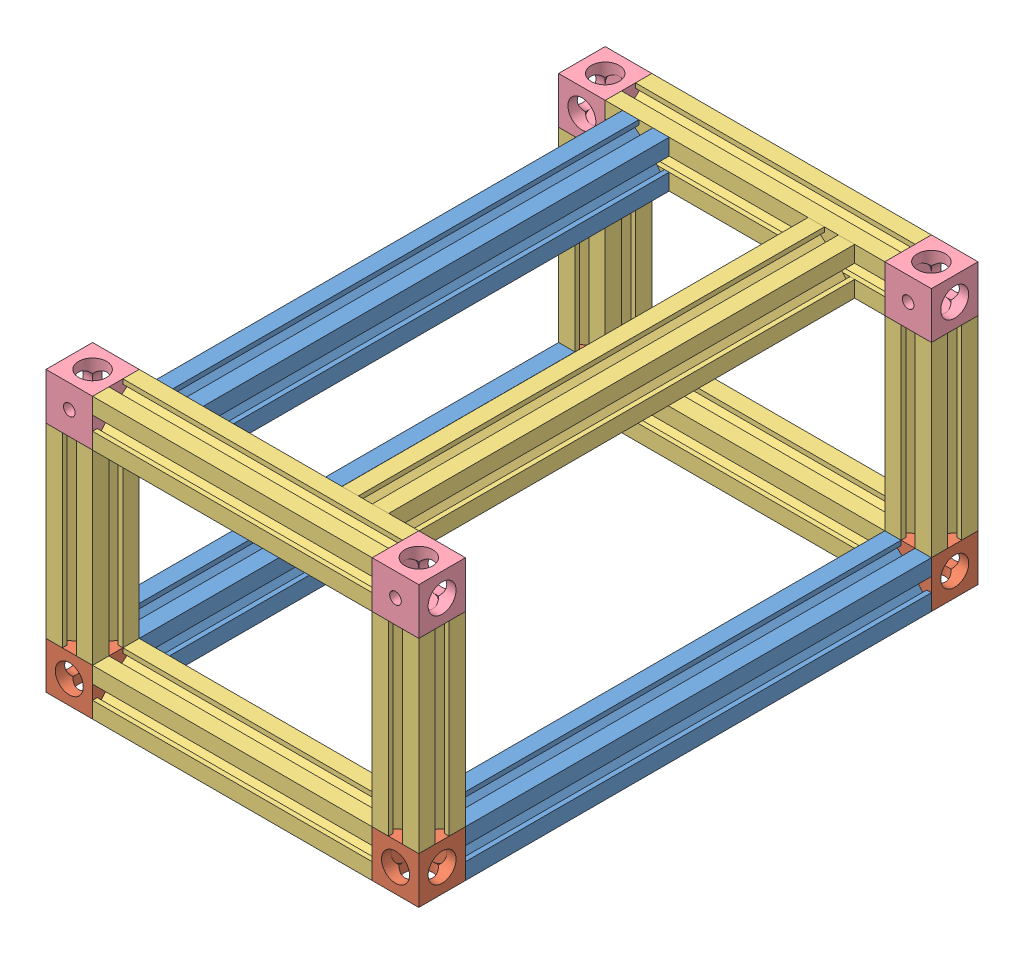
SolidWorks assembly Cabine, configuration Défaut. Lengths in mm.
Overall size (80 60 120).
20 component instances, 4 part files, 62 mates.
Components (placement in the parent):
- MakerBeam10x10x100-1: MakerBeam10x10x100 [Default] at origin size (10 10 100)
- MakerBeam10x10x100-2: MakerBeam10x10x100 [Default] at (-13.727 -50 0) size (10 10 100)
- MakerBeam10x10x100-3: MakerBeam10x10x100 [Default] at (56.273 -50 0) size (10 10 100)
- MakerBeamCornerCube-1: MakerBeamCornerCube [Default] at (61.273 -45 0) x (0 -1 0) z (0 0 -1) size (10 10 10)
- MakerBeamCornerCube-2: MakerBeamCornerCube [Default] at (-8.727 -55 0) x (-1 0 0) z (0 0 -1) size (10 10 10)
- MakerBeamCornerCube-3: MakerBeamCornerCube [Default] at (51.273 -55 100) size (10 10 10)
- MakerBeamCornerCube-4: MakerBeamCornerCube [Default] at (-18.727 -45 100) x (0 -1 0) z (0 0 1) size (10 10 10)
- Makerbeam50-1000mm-1: Makerbeam50-1000mm [60mm] at (51.273 -50 105) x (0 -1 0) z (-1 0 0) size (10 10 60)
- Makerbeam50-1000mm-2: Makerbeam50-1000mm [60mm] at (-8.727 -50 -5) x (0 1 0) z (1 0 0) size (10 10 60)
- Makerbeam50-1000mm-3: Makerbeam50-1000mm [60mm] at (-8.727 0 105) x (0 0 -1) z (1 0 0) size (10 10 60)
- Makerbeam50-1000mm-4: Makerbeam50-1000mm [60mm] at (51.273 0 -5) x (0 0 1) z (-1 0 0) size (10 10 60)
- MakerBeam-cube-1: MakerBeam-cube [Default] at (51.273 0 105) x (0 0 -1) z (1 0 0) size (10 10 10)
- MakerBeam-cube-2: MakerBeam-cube [Default] at (-8.727 0 -5) x (0 0 1) z (-1 0 0) size (10 10 10)
- MakerBeam-cube-3: MakerBeam-cube [Default] at (51.273 0 -5) x (0 0 -1) z (1 0 0) size (10 10 10)
- MakerBeam-cube-4: MakerBeam-cube [Default] at (-8.727 0 105) x (0 1 0) z (-1 0 0) size (10 10 10)
- Makerbeam50-1000mm-5: Makerbeam50-1000mm [40mm] at (56.273 -5 105) x (1 0 0) z (0 -1 0) size (10 10 40)
- Makerbeam50-1000mm-6: Makerbeam50-1000mm [40mm] at (-13.727 -5 105) x (1 0 0) z (0 -1 0) size (10 10 40)
- Makerbeam50-1000mm-7: Makerbeam50-1000mm [40mm] at (-13.727 -5 -5) x (1 0 0) z (0 -1 0) size (10 10 40)
- Makerbeam50-1000mm-8: Makerbeam50-1000mm [40mm] at (56.273 -5 -5) x (1 0 0) z (0 -1 0) size (10 10 40)
- Makerbeam50-1000mm-9: Makerbeam50-1000mm [100mm] at (39.8053 0 0) size (10 10 100)
Mates (geometry in assembly coordinates):
- Coïncidente1: coincident aligned: plane of MakerBeam10x10x100-1 through (0 0 0) normal (0 0 1); plane of assembly through (0 0 0) normal (0 0 1)
- Coïncidente2: coincident aligned: plane of MakerBeam10x10x100-1 through (0 0 0) normal (0 1 0); plane of assembly through (0 0 0) normal (0 1 0)
- Coïncidente3: coincident aligned: plane of MakerBeam10x10x100-1 through (0 0 0) normal (1 0 0); plane of assembly through (0 0 0) normal (1 0 0)
- Coïncidente4: coincident anti-aligned: plane of MakerBeam10x10x100-3 through (56.273 -50 100) normal (0 0 1); plane of MakerBeamCornerCube-3 through (51.273 -55 100) normal (0 0 -1)
- Coaxiale1: concentric anti-aligned: cylinder of MakerBeam10x10x100-3 through (56.273 -50 100) axis (0 0 -1) radius 1.25; cylinder of MakerBeamCornerCube-3 through (56.273 -50 100) axis (0 0 1) radius 1.5
- Coïncidente5: coincident anti-aligned: plane of MakerBeam10x10x100-3 through (56.273 -50 0) normal (0 0 -1); plane of MakerBeamCornerCube-1 through (61.273 -45 0) normal (0 0 1)
- Coaxiale2: concentric aligned: cylinder of MakerBeam10x10x100-3 through (56.273 -50 100) axis (0 0 -1) radius 1.25; cylinder of MakerBeamCornerCube-1 through (56.273 -50 0) axis (0 0 -1) radius 1.5
- Coïncidente6: coincident anti-aligned: plane of MakerBeam10x10x100-2 through (-13.727 -50 0) normal (0 0 -1); plane of MakerBeamCornerCube-2 through (-8.727 -55 0) normal (0 0 1)
- Coaxiale3: concentric aligned: cylinder of MakerBeam10x10x100-2 through (-13.727 -50 100) axis (0 0 -1) radius 1.25; cylinder of MakerBeamCornerCube-2 through (-13.727 -50 0) axis (0 0 -1) radius 1.5
- Coaxiale4: concentric anti-aligned: cylinder of MakerBeam10x10x100-2 through (-13.727 -50 100) axis (0 0 -1) radius 1.25; cylinder of MakerBeamCornerCube-4 through (-13.727 -50 100) axis (0 0 1) radius 1.5
- Coïncidente7: coincident anti-aligned: plane of MakerBeam10x10x100-2 through (-13.727 -50 100) normal (0 0 1); plane of MakerBeamCornerCube-4 through (-18.727 -45 100) normal (0 0 -1)
- Coïncidente8: coincident anti-aligned: plane of MakerBeamCornerCube-4 through (-8.727 -45 110) normal (1 0 0); plane of Makerbeam50-1000mm-1 through (-8.727 -50 105) normal (-1 0 0)
- Coaxiale5: concentric anti-aligned: cylinder of MakerBeamCornerCube-4 through (-8.727 -50 105) axis (-1 0 0) radius 1.5; cylinder of Makerbeam50-1000mm-1 through (-8.727 -50 105) axis (1 0 0) radius 1.25
- Coaxiale6: concentric aligned: cylinder of MakerBeamCornerCube-3 through (51.273 -50 105) axis (1 0 0) radius 1.5; cylinder of Makerbeam50-1000mm-1 through (-8.727 -50 105) axis (1 0 0) radius 1.25
- Coïncidente9: coincident anti-aligned: plane of MakerBeamCornerCube-3 through (51.273 -55 110) normal (-1 0 0); plane of Makerbeam50-1000mm-1 through (51.273 -50 105) normal (1 0 0)
- Coaxiale7: concentric anti-aligned: cylinder of MakerBeamCornerCube-1 through (51.273 -50 -5) axis (1 0 0) radius 1.5; cylinder of Makerbeam50-1000mm-2 through (51.273 -50 -5) axis (-1 0 0) radius 1.25
- Coïncidente10: coincident anti-aligned: plane of MakerBeamCornerCube-1 through (51.273 -45 -10) normal (-1 0 0); plane of Makerbeam50-1000mm-2 through (51.273 -50 -5) normal (1 0 0)
- Coaxiale9: concentric aligned: cylinder of MakerBeamCornerCube-2 through (-8.727 -50 -5) axis (-1 0 0) radius 1.5; cylinder of Makerbeam50-1000mm-2 through (51.273 -50 -5) axis (-1 0 0) radius 1.25
- Coïncidente12: coincident anti-aligned: plane of MakerBeamCornerCube-2 through (-8.727 -55 -10) normal (1 0 0); plane of Makerbeam50-1000mm-2 through (-8.727 -50 -5) normal (-1 0 0)
- Coïncidente13: coincident aligned: plane of Makerbeam50-1000mm-2 through (51.273 -45 0) normal (0 1 0); plane of MakerBeamCornerCube-2 through (-8.727 -45 -10) normal (0 1 0)
- Coïncidente14: coincident aligned: plane of MakerBeam10x10x100-2 through (-8.727 -45 100) normal (0 1 0); plane of MakerBeamCornerCube-2 through (-8.727 -45 -10) normal (0 1 0)
- Coïncidente15: coincident aligned: plane of MakerBeam10x10x100-3 through (51.273 -45 100) normal (0 1 0); plane of MakerBeamCornerCube-1 through (61.273 -45 -10) normal (0 1 0)
- Coïncidente16: coincident aligned: plane of MakerBeamCornerCube-1 through (61.273 -45 -10) normal (0 1 0); plane of Makerbeam50-1000mm-2 through (51.273 -45 -6.5) normal (0 1 0)
- Coïncidente17: coincident aligned: plane of MakerBeamCornerCube-3 through (51.273 -45 110) normal (0 1 0); plane of Makerbeam50-1000mm-1 through (-8.727 -45 100) normal (0 1 0)
- Coïncidente18: coincident aligned: plane of MakerBeam10x10x100-3 through (51.273 -45 100) normal (0 1 0); plane of MakerBeamCornerCube-3 through (51.273 -45 110) normal (0 1 0)
- Coïncidente19: coincident aligned: plane of MakerBeamCornerCube-4 through (-18.727 -45 110) normal (0 1 0); plane of Makerbeam50-1000mm-1 through (-8.727 -45 100) normal (0 1 0)
- Coïncidente21: coincident aligned: plane of MakerBeam10x10x100-2 through (-8.727 -45 100) normal (0 1 0); plane of MakerBeamCornerCube-4 through (-18.727 -45 110) normal (0 1 0)
- Coïncidente22: coincident anti-aligned: plane of Makerbeam50-1000mm-3 through (51.273 0 105) normal (1 0 0); plane of MakerBeam-cube-1 through (51.273 0 105) normal (-1 0 0)
- Coaxiale10: concentric anti-aligned: cylinder of Makerbeam50-1000mm-3 through (51.273 0 105) axis (-1 0 0) radius 1.25; cylinder of MakerBeam-cube-1 through (61.273 0 105) axis (1 0 0) radius 1.25
- Coïncidente23: coincident anti-aligned: plane of Makerbeam50-1000mm-3 through (-8.727 0 105) normal (-1 0 0); plane of MakerBeam-cube-4 through (-8.727 0 105) normal (1 0 0)
- Coaxiale11: concentric aligned: cylinder of Makerbeam50-1000mm-3 through (51.273 0 105) axis (-1 0 0) radius 1.25; cylinder of MakerBeam-cube-4 through (-18.727 0 105) axis (-1 0 0) radius 1.25
- Coïncidente28: coincident anti-aligned: plane of Makerbeam50-1000mm-4 through (-8.727 0 -5) normal (-1 0 0); plane of MakerBeam-cube-2 through (-8.727 0 -5) normal (1 0 0)
- Coaxiale17: concentric anti-aligned: cylinder of Makerbeam50-1000mm-4 through (-8.727 0 -5) axis (1 0 0) radius 1.25; cylinder of MakerBeam-cube-2 through (-18.727 0 -5) axis (-1 0 0) radius 1.25
- Coïncidente29: coincident anti-aligned: plane of Makerbeam50-1000mm-4 through (51.273 0 -5) normal (1 0 0); plane of MakerBeam-cube-3 through (51.273 0 -5) normal (-1 0 0)
- Coaxiale18: concentric aligned: cylinder of Makerbeam50-1000mm-4 through (-8.727 0 -5) axis (1 0 0) radius 1.25; cylinder of MakerBeam-cube-3 through (61.273 0 -5) axis (1 0 0) radius 1.25
- Coaxiale19: concentric anti-aligned: cylinder of MakerBeamCornerCube-1 through (56.273 -45 -5) axis (0 -1 0) radius 1.5; cylinder of Makerbeam50-1000mm-8 through (56.273 -45 -5) axis (0 1 0) radius 1.25
- Coaxiale20: concentric anti-aligned: cylinder of MakerBeamCornerCube-2 through (-13.727 -45 -5) axis (0 -1 0) radius 1.5; cylinder of Makerbeam50-1000mm-7 through (-13.727 -45 -5) axis (0 1 0) radius 1.25
- Coaxiale21: concentric anti-aligned: cylinder of MakerBeamCornerCube-3 through (56.273 -45 105) axis (0 -1 0) radius 1.5; cylinder of Makerbeam50-1000mm-5 through (56.273 -45 105) axis (0 1 0) radius 1.25
- Coaxiale22: concentric anti-aligned: cylinder of MakerBeamCornerCube-4 through (-13.727 -45 105) axis (0 -1 0) radius 1.5; cylinder of Makerbeam50-1000mm-6 through (-13.727 -45 105) axis (0 1 0) radius 1.25
- Coïncidente30: coincident anti-aligned: plane of MakerBeamCornerCube-4 through (-18.727 -45 110) normal (0 1 0); plane of Makerbeam50-1000mm-6 through (-13.727 -45 105) normal (0 -1 0)
- Coïncidente31: coincident anti-aligned: plane of MakerBeamCornerCube-3 through (51.273 -45 110) normal (0 1 0); plane of Makerbeam50-1000mm-5 through (56.273 -45 105) normal (0 -1 0)
- Coïncidente33: coincident anti-aligned: plane of MakerBeamCornerCube-1 through (61.273 -45 -10) normal (0 1 0); plane of Makerbeam50-1000mm-8 through (56.273 -45 -5) normal (0 -1 0)
- Coïncidente34: coincident anti-aligned: plane of MakerBeamCornerCube-2 through (-8.727 -45 -10) normal (0 1 0); plane of Makerbeam50-1000mm-7 through (-13.727 -45 -5) normal (0 -1 0)
- Coïncidente35: coincident anti-aligned: plane of MakerBeam-cube-4 through (-18.727 -5 110) normal (0 -1 0); plane of Makerbeam50-1000mm-5 through (56.273 -5 105) normal (0 1 0)
- Coaxiale23: concentric anti-aligned: cylinder of MakerBeam-cube-1 through (56.273 -5 105) axis (0 -1 0) radius 1.25; cylinder of Makerbeam50-1000mm-5 through (56.273 -45 105) axis (0 1 0) radius 1.25
- Coïncidente36: coincident anti-aligned: plane of MakerBeam-cube-2 through (-18.727 -5 0) normal (0 -1 0); plane of Makerbeam50-1000mm-7 through (-13.727 -5 -5) normal (0 1 0)
- Coaxiale24: concentric anti-aligned: cylinder of MakerBeam-cube-2 through (-13.727 -5 -5) axis (0 -1 0) radius 1.25; cylinder of Makerbeam50-1000mm-7 through (-13.727 -45 -5) axis (0 1 0) radius 1.25
- Coïncidente37: coincident anti-aligned: plane of MakerBeam-cube-4 through (-18.727 -5 110) normal (0 -1 0); plane of Makerbeam50-1000mm-6 through (-13.727 -5 105) normal (0 1 0)
- Coaxiale25: concentric aligned: cylinder of MakerBeam-cube-4 through (-13.727 5 105) axis (0 1 0) radius 1.25; cylinder of Makerbeam50-1000mm-6 through (-13.727 -45 105) axis (0 1 0) radius 1.25
- Coïncidente38: coincident anti-aligned: plane of MakerBeam-cube-3 through (61.273 -5 -10) normal (0 -1 0); plane of Makerbeam50-1000mm-8 through (56.273 -5 -5) normal (0 1 0)
- Coaxiale28: concentric anti-aligned: cylinder of MakerBeam-cube-3 through (56.273 -5 -5) axis (0 -1 0) radius 1.25; cylinder of Makerbeam50-1000mm-8 through (56.273 -45 -5) axis (0 1 0) radius 1.25
- Coïncidente39: coincident anti-aligned: plane of MakerBeam10x10x100-1 through (0 0 100) normal (0 0 1); plane of Makerbeam50-1000mm-3 through (51.273 -1.5 100) normal (0 0 -1)
- Coïncidente40: coincident anti-aligned: plane of MakerBeam10x10x100-1 through (0 0 0) normal (0 0 -1); plane of Makerbeam50-1000mm-4 through (-8.727 -1.5 0) normal (0 0 1)
- Coïncidente41: coincident aligned: plane of MakerBeam10x10x100-1 through (5 5 100) normal (0 1 0); plane of Makerbeam50-1000mm-4 through (-8.727 5 -3.5) normal (0 1 0)
- Coïncidente42: coincident aligned: plane of MakerBeamCornerCube-3 through (51.273 -55 110) normal (0 0 1); plane of Makerbeam50-1000mm-5 through (51.273 -45 110) normal (0 0 1)
- Coïncidente43: coincident aligned: plane of MakerBeamCornerCube-4 through (-18.727 -45 110) normal (0 0 1); plane of Makerbeam50-1000mm-6 through (-12.227 -45 110) normal (0 0 1)
- Coïncidente44: coincident aligned: plane of Makerbeam50-1000mm-3 through (51.273 1.5 110) normal (0 0 1); plane of MakerBeam-cube-4 through (-18.727 5 110) normal (0 0 1)
- Coïncidente46: coincident aligned: plane of Makerbeam50-1000mm-4 through (-8.727 5 -3.5) normal (0 1 0); plane of MakerBeam-cube-3 through (61.273 5 -10) normal (0 1 0)
- Coïncidente47: coincident aligned: plane of MakerBeamCornerCube-1 through (61.273 -45 -10) normal (1 0 0); plane of Makerbeam50-1000mm-8 through (61.273 -45 0) normal (1 0 0)
- Coïncidente48: coincident aligned: plane of MakerBeamCornerCube-2 through (-18.727 -55 -10) normal (-1 0 0); plane of Makerbeam50-1000mm-7 through (-18.727 -45 -3.5) normal (-1 0 0)
- Coïncidente51: coincident aligned: plane of Makerbeam50-1000mm-3 through (51.273 5 103.5) normal (0 1 0); plane of Makerbeam50-1000mm-9 through (41.3053 5 100) normal (0 1 0)
- Coïncidente52: coincident anti-aligned: plane of Makerbeam50-1000mm-3 through (51.273 -1.5 100) normal (0 0 -1); plane of Makerbeam50-1000mm-9 through (39.8053 0 100) normal (0 0 1)
